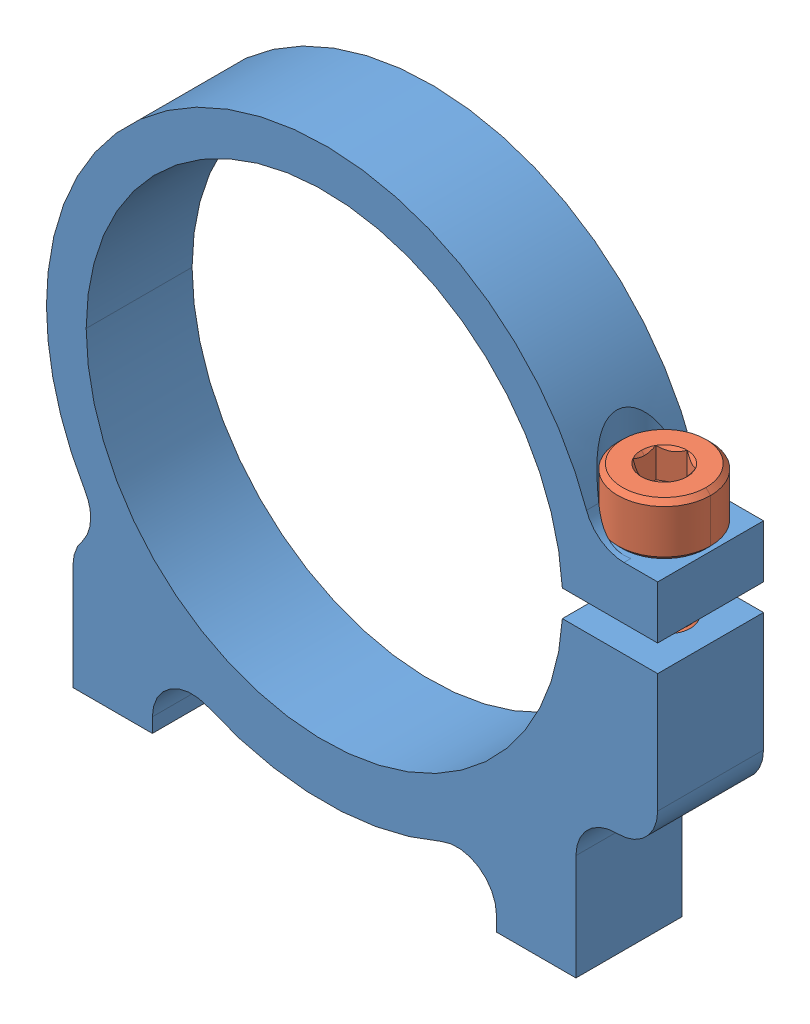
SolidWorks assembly 1-Side, 2-Post Clamping Mount (36mm Bore)1400-0032-0036, configuration Default. Lengths in mm.
Overall size (46.17 45 8).
2 component instances, 2 part files, 0 mates.
Components (placement in the parent):
- 1400-0032-0036.STEP-1: 1400-0032-0036.STEP [Default] at (-30.3345 5.5593 8.2328) size (46.17 45 8)
- 2800-0004-0012_90128A207.STEP-1: 2800-0004-0012_90128A207.STEP [Default] at (-8.6623 -1.4407 12.2328) x (1 0 0) z (0 -1 0) size (7 7 16.01)
